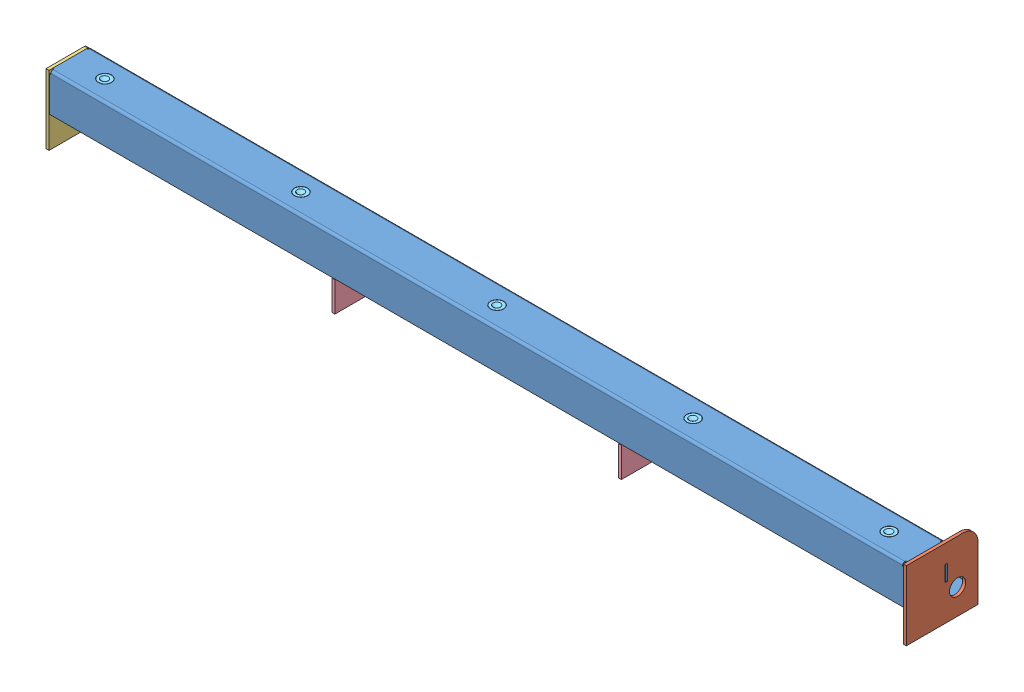
SolidWorks assembly 凸輪軌道座-右, configuration 預設. Lengths in mm.
Overall size (856 69.43 71.7).
10 component instances, 5 part files, 12 mates.
Components (placement in the parent):
- LB-A54-12-3-1: LB-A54-12-3 [預設] at (-421.8803 -71.8874 -5.1) size (856 68.08 70.64)
- LB-A54-12-4-1: LB-A54-12-4 [預設] at (431.1197 -45.8274 36.1) x (0 0 -1) z (1 0 0) size (71.3 69 3)
- LB-A54-12-5-1: LB-A54-12-5 [預設] at (-421.8803 -45.8274 35.7) x (0 0 -1) z (1 0 0) size (71.3 69 3)
- LB-A54-12-6-1: LB-A54-12-6 [預設] at (147.1197 -44.9474 35.4) x (0 0 -1) z (1 0 0) size (68.5 66.5 3)
- LB-A54-12-6-2: LB-A54-12-6 [預設] at (-137.8803 -44.9474 35.4) x (0 0 -1) z (1 0 0) size (68.5 66.5 3)
- 2分半點焊螺帽-1: 2分半點焊螺帽 [預設] at (-383.8803 15.6726 15.11) size (18.22 7.93 18.22)
- 2分半點焊螺帽-2: 2分半點焊螺帽 [預設] at (-188.8803 15.6726 15.11) size (18.22 7.93 18.22)
- 2分半點焊螺帽-3: 2分半點焊螺帽 [預設] at (6.1197 15.6726 15.11) size (18.22 7.93 18.22)
- 2分半點焊螺帽-4: 2分半點焊螺帽 [預設] at (201.1197 15.6726 15.11) size (18.22 7.93 18.22)
- 2分半點焊螺帽-5: 2分半點焊螺帽 [預設] at (396.1197 15.6726 15.11) size (18.22 7.93 18.22)
Mates (geometry in assembly coordinates):
- 重合/共線/共點1: coincident anti-aligned: plane of LB-A54-12-3-1 through (431.1197 20.8726 -1.64) normal (1 0 0); plane of LB-A54-12-4-1 through (431.1197 8.1726 -20.2) normal (-1 0 0)
- 重合/共線/共點2: coincident anti-aligned: plane of LB-A54-12-3-1 through (-418.8803 21.2126 -5.1) normal (0 0 -1); plane of LB-A54-12-4-1 through (434.1197 4.7726 -5.1) normal (0 0 1)
- 重合/共線/共點3: coincident aligned: plane of LB-A54-12-3-1 through (-418.8803 23.1726 -3.14) normal (0 1 0); plane of LB-A54-12-4-1 through (434.1197 23.1726 -20.2) normal (0 1 0)
- 重合/共線/共點4: coincident anti-aligned: plane of LB-A54-12-3-1 through (-418.8803 20.8726 31.86) normal (-1 0 0); plane of LB-A54-12-5-1 through (-418.8803 -21.6274 -30.6) normal (1 0 0)
- 重合/共線/共點5: coincident anti-aligned: plane of LB-A54-12-3-1 through (-418.8803 21.2126 -2.8) normal (0 0 1); plane of LB-A54-12-5-1 through (-418.8803 -26.6274 -2.8) normal (0 0 -1)
- 重合/共線/共點6: coincident aligned: plane of LB-A54-12-3-1 through (-418.8803 23.1726 -3.14) normal (0 1 0); plane of LB-A54-12-5-1 through (-418.8803 23.1726 -2.3) normal (0 1 0)
- 重合/共線/共點7: coincident anti-aligned: plane of LB-A54-12-6-1 through (150.1197 -32.2474 -30.1) normal (0 1 0); plane of LB-A54-12-3-1 through (-418.8803 -32.2474 46.74) normal (0 -1 0)
- 重合/共線/共點8: coincident anti-aligned: plane of LB-A54-12-6-1 through (150.1197 -32.2474 -2.8) normal (0 0 -1); plane of LB-A54-12-3-1 through (-418.8803 21.2126 -2.8) normal (0 0 1)
- 平行相距1: distance = 281 mm anti-aligned: plane of LB-A54-12-4-1 through (431.1197 8.1726 -20.2) normal (-1 0 0); plane of LB-A54-12-6-1 through (150.1197 -35.2474 -30.1) normal (1 0 0)
- 同軸心1: concentric aligned: cylinder of LB-A54-12-3-1 through (-383.8803 20.8726 15.11) axis (0 1 0) radius 6.6; cylinder of 2分半點焊螺帽-1 through (-383.8803 25.6407 15.11) axis (0 1 0) radius 6.5
- 重合/共線/共點9: coincident aligned: plane of LB-A54-12-3-1 through (-418.8803 23.1726 -3.14) normal (0 1 0); plane of 2分半點焊螺帽-1 through (-383.8803 23.1726 5.9176) normal (0 1 0)
- 局部直線複製2: unknown: line of LB-A54-12-3-1 through (-417.4193 20.8726 33.02) axis (1 0 0)
